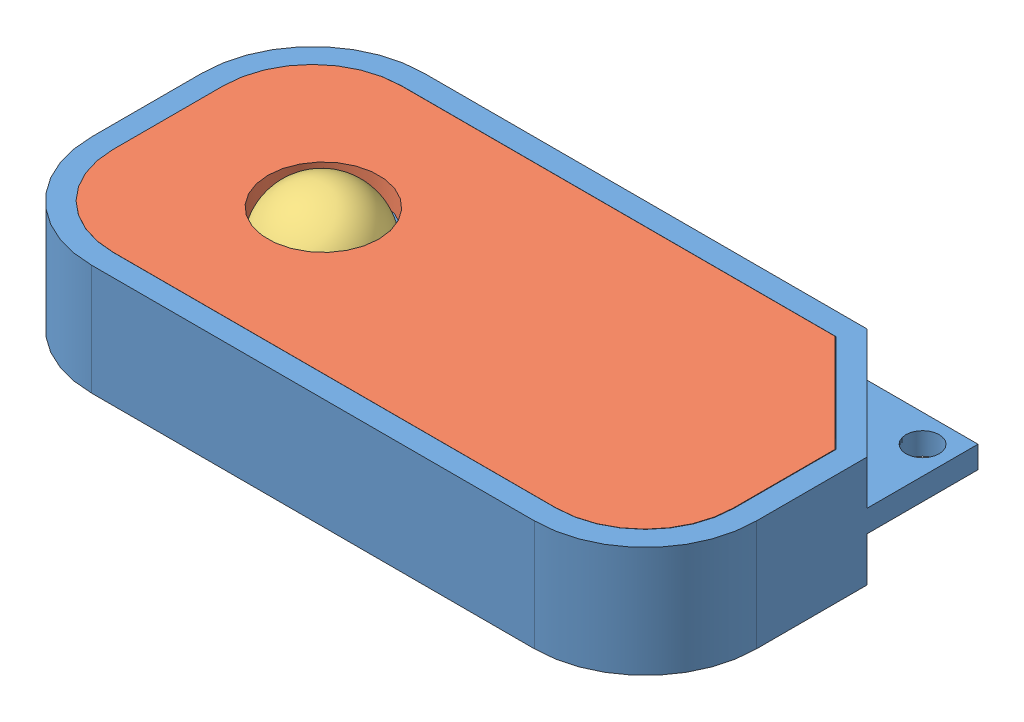
SolidWorks assembly Assem, configuration Default. Lengths in mm.
Overall size (60 11.88 31).
3 component instances, 3 part files, 0 mates.
Components (placement in the parent):
- Part1-1: Part1 [Default] at (27.606 21.9747 55.7079) size (60 10 31)
- top-1: top [Default] at (55.7572 29.9879 32.2393) x (1 0 0) z (0 1 0) size (56 26 2)
- Led-1: Led [Default] at (10.8476 22.7533 48.1628) size (10 11.1 10)
